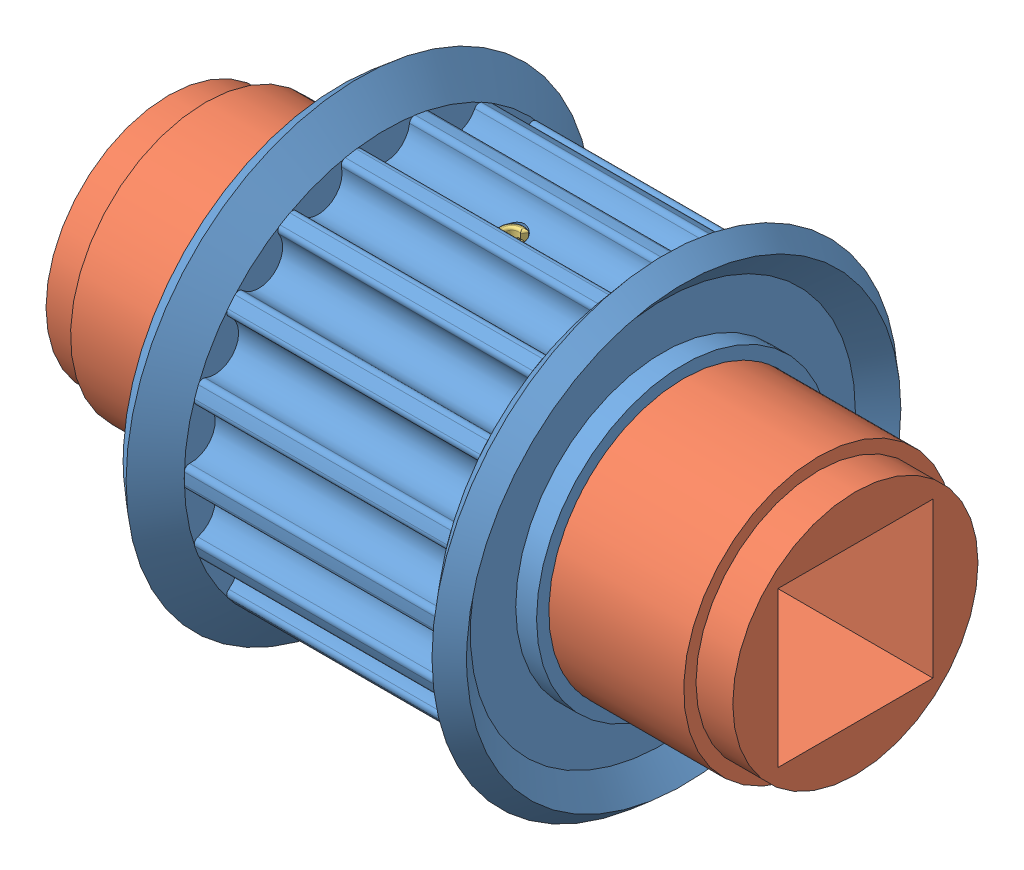
SolidWorks assembly Pulley_MoldedAssm2, configuration Default. Lengths in mm.
Overall size (28 19 19).
3 component instances, 3 part files, 5 mates.
Components (placement in the parent):
- GT3x18_GPA18GT3090-A-H8-1: GT3x18_GPA18GT3090-A-H8 [Machined] at origin size (14 19 19)
- Square_Insert^Pulley_MoldedAssm2-1: Square_Insert^Pulley_MoldedAssm2 [Default] at origin size (28 11 11) (virtual)
- SpringPin_1x4_91611A065-1: SpringPin_1x4_91611A065 [Default] at (0 5.16 0) x (0 -1 0) z (0 0 1) size (4.02 1.01 1)
Mates (geometry in assembly coordinates):
- Coincident1: coincident aligned: plane of GT3x18_GPA18GT3090-A-H8-1 through (0 0 0) normal (0 0 1); plane of assembly through (0 0 0) normal (0 0 1)
- Coincident2: coincident aligned: plane of GT3x18_GPA18GT3090-A-H8-1 through (0 0 0) normal (0 1 0); plane of assembly through (0 0 0) normal (0 1 0)
- Coincident3: coincident aligned: plane of GT3x18_GPA18GT3090-A-H8-1 through (0 0 0) normal (1 0 0); plane of assembly through (0 0 0) normal (1 0 0)
- Concentric1: concentric anti-aligned: cylinder of GT3x18_GPA18GT3090-A-H8-1 through (0 9.5 0) axis (0 -1 0) radius 0.5; cylinder of SpringPin_1x4_91611A065-1 through (0 5.16 0) axis (0 1 0) radius 0.5
- Coincident4: coincident aligned: plane of Square_Insert^Pulley_MoldedAssm2-1 through (14 3.16 -3.16) normal (0 -1 0); plane of SpringPin_1x4_91611A065-1 through (0.25 3.16 -0.433) normal (0 -1 0)
